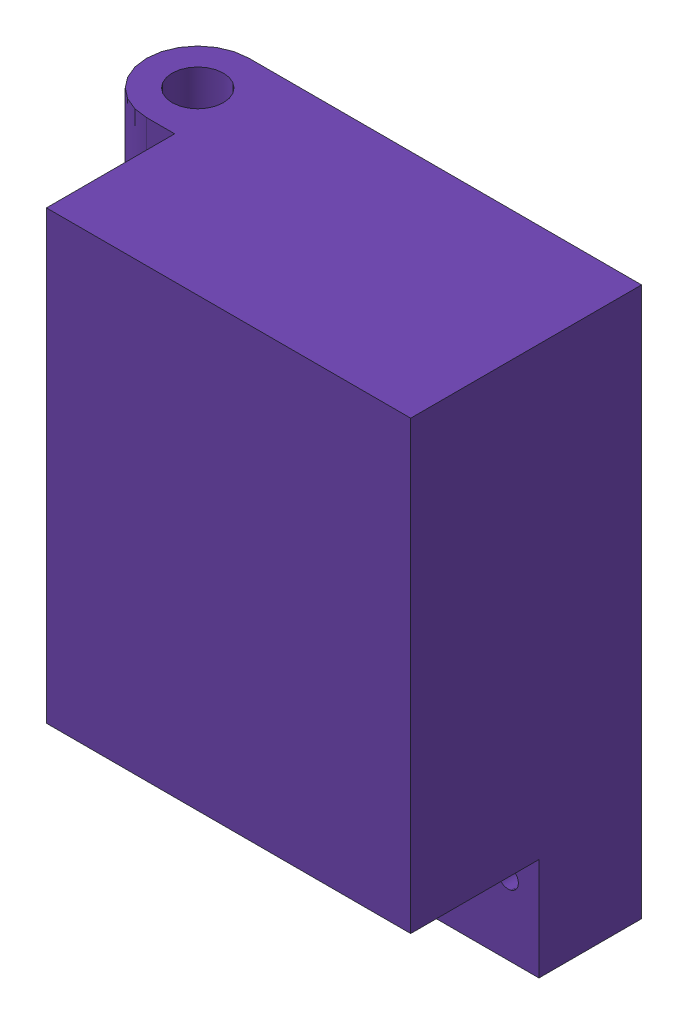
SolidWorks assembly LoRa_Balloon, configuration Default. Lengths in mm.
Overall size (43.25 53.5 22.5).
126 component instances, 18 part files, 6 mates.
Components (placement in the parent):
- LoRa_Balloon.step-1: LoRa_Balloon.step [Default] at origin size (30 47 5)
  - TSX-3225.step-1: TSX-3225.step [Default] at (108.5095 -135.9864 1.65) x (1 0 0) z (0 -1 0) size (3.2 0.6 2.5)
    - SOLID.step-1: SOLID.step [Default] at origin size (3.2 0.6 2.5)
  - ublox_MAX_M8C.step-1: ublox_MAX_M8C.step [Default] at (106.83 -119.32 -0.05) x (0 -1 0) z (1 0 0) size (9.72 2.21 10.1)
    - COMPOUND.step-1: COMPOUND.step [Default] at origin size (9.72 2.21 10.1)
  - 0402_C.step-1: 0402_C.step [Default] at (107.16 -138.61 1.65) x (1 0 0) z (0 -1 0) size (0.9 0.3 0.5)
    - COMPOUND-0.step-1: COMPOUND-0.step [Default] at origin size (0.9 0.3 0.5)
  - SC-70.step-1: SC-70.step [Default] at (116.0558 -117.9372 1.65) x (1 0 0) z (0 -1 0) size (2.05 0.9 2.1)
    - COMPOUND-1.step-1: COMPOUND-1.step [Default] at origin size (2.05 0.9 2.1)
  - DFN-8.step-1: DFN-8.step [Default] at (122.5624 -127.2782 1.65) x (-1 0 0) z (0 1 0) size (2.02 0.86 2)
    - COMPOUND-2.step-1: COMPOUND-2.step [Default] at origin size (2.02 0.86 2)
  - DFN-8.step-2: DFN-8.step [Default] at (121.4762 -122.3263 1.65) x (1 0 0) z (0 -1 0) size (2.02 0.86 2)
    - COMPOUND-2.step-1: COMPOUND-2.step [Default] at origin size (2.02 0.86 2)
  - SAW_filter.step-1: SAW_filter.step [Default] at (115.95 -106.9 1.65) x (1 0 0) z (0 -1 0) size (3.02 1.11 3.02)
    - COMPOUND-3.step-1: COMPOUND-3.step [Default] at origin size (3.02 1.11 3.02)
  - XCL205.step-1: XCL205.step [Default] at (125.85 -135.26 1.65) x (0 1 0) z (1 0 0) size (2.5 1.05 2)
    - COMPOUND-4.step-1: COMPOUND-4.step [Default] at origin size (2.5 1.05 2)
  - 7A_crystal.step-1: 7A_crystal.step [Default] at (104.33 -136.88 -0.05) x (1 0 0) z (0 1 0) size (5 1.2 3.2)
    - SOLID-5.step-1: SOLID-5.step [Default] at origin size (5 1.2 3.2)
  - Chip_antenna.step-1: Chip_antenna.step [Default] at (103.53 -105.26 -0.05) x (0 -1 0) z (1 0 0) size (7 0.85 2)
    - COMPOUND-6.step-1: COMPOUND-6.step [Default] at origin size (7 0.85 2)
  - Chip_antenna.step-2: Chip_antenna.step [Default] at (125.75 -102.8 1.65) x (-1 0 0) z (0 1 0) size (7 0.85 2)
    - COMPOUND-6.step-1: COMPOUND-6.step [Default] at origin size (7 0.85 2)
  - SX1272.step-1: SX1272.step [Default] at (115.3441 -133.9037 1.65) x (1 0 0) z (0 -1 0) size (6.02 0.92 6.02)
    - COMPOUND-7.step-1: COMPOUND-7.step [Default] at origin size (6.02 0.92 6.02)
  - 0402_C.step-2: 0402_C.step [Default] at (109.29 -133.64 1.65) x (0 -1 0) z (-1 0 0) size (0.9 0.3 0.5)
    - COMPOUND-0.step-1: COMPOUND-0.step [Default] at origin size (0.9 0.3 0.5)
  - ATMega-328P-MMH.step-1: ATMega-328P-MMH.step [Default] at (105.5 -131.22 -0.05) x (1 0 0) z (0 1 0) size (4.02 0.92 4.02)
    - COMPOUND-8.step-1: COMPOUND-8.step [Default] at origin size (4.02 0.92 4.02)
  - 0805_C.step-1: 0805_C.step [Default] at (109.5737 -129.9064 1.65) x (0 1 0) z (1 0 0) size (1.55 0.8 1.25)
    - COMPOUND-9.step-1: COMPOUND-9.step [Default] at origin size (1.55 0.8 1.25)
  - 0402_C.step-3: 0402_C.step [Default] at (120.5719 -118.3812 1.65) x (0 1 0) z (1 0 0) size (0.9 0.3 0.5)
    - COMPOUND-0.step-1: COMPOUND-0.step [Default] at origin size (0.9 0.3 0.5)
  - 0402_C.step-4: 0402_C.step [Default] at (122.8782 -119.8472 1.65) x (0 1 0) z (1 0 0) size (0.9 0.3 0.5)
    - COMPOUND-0.step-1: COMPOUND-0.step [Default] at origin size (0.9 0.3 0.5)
  - 0402_C.step-5: 0402_C.step [Default] at (124.1736 -119.8472 1.65) x (0 1 0) z (1 0 0) size (0.9 0.3 0.5)
    - COMPOUND-0.step-1: COMPOUND-0.step [Default] at origin size (0.9 0.3 0.5)
  - 0402_C.step-6: 0402_C.step [Default] at (113.8714 -116.9872 1.65) x (-1 0 0) z (0 1 0) size (0.9 0.3 0.5)
    - COMPOUND-0.step-1: COMPOUND-0.step [Default] at origin size (0.9 0.3 0.5)
  - 0603_C.step-1: 0603_C.step [Default] at (125.93 -132.62 1.65) x (1 0 0) z (0 -1 0) size (1.2 0.8 0.8)
    - COMPOUND-10.step-1: COMPOUND-10.step [Default] at origin size (1.2 0.8 0.8)
  - 0603_C.step-2: 0603_C.step [Default] at (123.59 -138.21 1.65) x (-1 0 0) z (0 1 0) size (1.2 0.8 0.8)
    - COMPOUND-10.step-1: COMPOUND-10.step [Default] at origin size (1.2 0.8 0.8)
  - 0402_C.step-7: 0402_C.step [Default] at (103.98 -126.99 -0.05) x (-1 0 0) z (0 -1 0) size (0.9 0.3 0.5)
    - COMPOUND-0.step-1: COMPOUND-0.step [Default] at origin size (0.9 0.3 0.5)
  - 0402_C.step-8: 0402_C.step [Default] at (103.59 -139.5 -0.05) x (0 1 0) z (-1 0 0) size (0.9 0.3 0.5)
    - COMPOUND-0.step-1: COMPOUND-0.step [Default] at origin size (0.9 0.3 0.5)
  - 0402_C.step-9: 0402_C.step [Default] at (104.89 -139.5 -0.05) x (0 1 0) z (-1 0 0) size (0.9 0.3 0.5)
    - COMPOUND-0.step-1: COMPOUND-0.step [Default] at origin size (0.9 0.3 0.5)
  - 0402_C.step-10: 0402_C.step [Default] at (110.04 -127.13 -0.05) x (0 -1 0) z (1 0 0) size (0.9 0.3 0.5)
    - COMPOUND-0.step-1: COMPOUND-0.step [Default] at origin size (0.9 0.3 0.5)
  - 0402_L.step-1: 0402_L.step [Default] at (113.6276 -121.7857 1.65) x (0 -1 0) z (-1 0 0) size (0.9 0.3 0.5)
    - COMPOUND-11.step-1: COMPOUND-11.step [Default] at origin size (0.9 0.3 0.5)
  - 0402_L.step-2: 0402_L.step [Default] at (113.0942 -129.3519 1.65) x (0 -1 0) z (-1 0 0) size (0.9 0.3 0.5)
    - COMPOUND-11.step-1: COMPOUND-11.step [Default] at origin size (0.9 0.3 0.5)
  - 0402_C.step-11: 0402_C.step [Default] at (117.1611 -120.1876 1.65) x (1 0 0) z (0 -1 0) size (0.9 0.3 0.5)
    - COMPOUND-0.step-1: COMPOUND-0.step [Default] at origin size (0.9 0.3 0.5)
  - 0402_C.step-12: 0402_C.step [Default] at (111.2196 -130.757 1.65) x (0 1 0) z (1 0 0) size (0.9 0.3 0.5)
    - COMPOUND-0.step-1: COMPOUND-0.step [Default] at origin size (0.9 0.3 0.5)
  - 0402_C.step-13: 0402_C.step [Default] at (117.0293 -121.7606 1.65) x (-0.707107 0.707107 0) z (0.707107 0.707107 0) size (0.9 0.3 0.5)
    - COMPOUND-0.step-1: COMPOUND-0.step [Default] at origin size (0.9 0.3 0.5)
  - 0402_C.step-14: 0402_C.step [Default] at (110.8869 -132.3542 1.65) x (-1 0 0) z (0 1 0) size (0.9 0.3 0.5)
    - COMPOUND-0.step-1: COMPOUND-0.step [Default] at origin size (0.9 0.3 0.5)
  - 0402_C.step-15: 0402_C.step [Default] at (111.6739 -128.28 1.65) x (-1 0 0) z (0 1 0) size (0.9 0.3 0.5)
    - COMPOUND-0.step-1: COMPOUND-0.step [Default] at origin size (0.9 0.3 0.5)
  - 0402_C.step-16: 0402_C.step [Default] at (110.8916 -133.4108 1.65) x (-1 0 0) z (0 1 0) size (0.9 0.3 0.5)
    - COMPOUND-0.step-1: COMPOUND-0.step [Default] at origin size (0.9 0.3 0.5)
  - 0402_C.step-17: 0402_C.step [Default] at (111.6739 -129.357 1.65) x (-1 0 0) z (0 1 0) size (0.9 0.3 0.5)
    - COMPOUND-0.step-1: COMPOUND-0.step [Default] at origin size (0.9 0.3 0.5)
  - 0402_C.step-18: 0402_C.step [Default] at (122.95 -135.86 1.65) x (1 0 0) z (0 -1 0) size (0.9 0.3 0.5)
    - COMPOUND-0.step-1: COMPOUND-0.step [Default] at origin size (0.9 0.3 0.5)
  - 0402_C.step-19: 0402_C.step [Default] at (124.6105 -122.5316 1.65) x (0 1 0) z (1 0 0) size (0.9 0.3 0.5)
    - COMPOUND-0.step-1: COMPOUND-0.step [Default] at origin size (0.9 0.3 0.5)
  - 0402_C.step-20: 0402_C.step [Default] at (125.0605 -123.9265 1.65) x (1 0 0) z (0 -1 0) size (0.9 0.3 0.5)
    - COMPOUND-0.step-1: COMPOUND-0.step [Default] at origin size (0.9 0.3 0.5)
  - 0402_C.step-21: 0402_C.step [Default] at (124.6105 -125.3366 1.65) x (0 1 0) z (1 0 0) size (0.9 0.3 0.5)
    - COMPOUND-0.step-1: COMPOUND-0.step [Default] at origin size (0.9 0.3 0.5)
  - 0402_C.step-22: 0402_C.step [Default] at (125.276 -129.0141 1.65) x (0 1 0) z (1 0 0) size (0.9 0.3 0.5)
    - COMPOUND-0.step-1: COMPOUND-0.step [Default] at origin size (0.9 0.3 0.5)
  - 0402_C.step-23: 0402_C.step [Default] at (109.06 -138.03 1.65) x (1 0 0) z (0 -1 0) size (0.9 0.3 0.5)
    - COMPOUND-0.step-1: COMPOUND-0.step [Default] at origin size (0.9 0.3 0.5)
  - 0402_C.step-24: 0402_C.step [Default] at (120.5135 -129.5805 1.65) x (0 -1 0) z (-1 0 0) size (0.9 0.3 0.5)
    - COMPOUND-0.step-1: COMPOUND-0.step [Default] at origin size (0.9 0.3 0.5)
  - 0402_C.step-25: 0402_C.step [Default] at (113.6957 -127.9549 1.65) x (-1 0 0) z (0 1 0) size (0.9 0.3 0.5)
    - COMPOUND-0.step-1: COMPOUND-0.step [Default] at origin size (0.9 0.3 0.5)
  - 0402_C.step-26: 0402_C.step [Default] at (121.5244 -129.5805 1.65) x (0 -1 0) z (-1 0 0) size (0.9 0.3 0.5)
    - COMPOUND-0.step-1: COMPOUND-0.step [Default] at origin size (0.9 0.3 0.5)
  - 0402_C.step-27: 0402_C.step [Default] at (114.1457 -126.5499 1.65) x (0 -1 0) z (-1 0 0) size (0.9 0.3 0.5)
    - COMPOUND-0.step-1: COMPOUND-0.step [Default] at origin size (0.9 0.3 0.5)
  - 0402_C.step-28: 0402_C.step [Default] at (117.4477 -127.0807 1.65) x (0 1 0) z (1 0 0) size (0.9 0.3 0.5)
    - COMPOUND-0.step-1: COMPOUND-0.step [Default] at origin size (0.9 0.3 0.5)
  - 0402_C.step-29: 0402_C.step [Default] at (118.9103 -127.5282 1.65) x (1 0 0) z (0 -1 0) size (0.9 0.3 0.5)
    - COMPOUND-0.step-1: COMPOUND-0.step [Default] at origin size (0.9 0.3 0.5)
  - 0402_C.step-30: 0402_C.step [Default] at (113.6881 -123.3804 1.65) x (-1 0 0) z (0 1 0) size (0.9 0.3 0.5)
    - COMPOUND-0.step-1: COMPOUND-0.step [Default] at origin size (0.9 0.3 0.5)
  - 0402_C.step-31: 0402_C.step [Default] at (114.674 -121.7857 1.65) x (0 -1 0) z (-1 0 0) size (0.9 0.3 0.5)
    - COMPOUND-0.step-1: COMPOUND-0.step [Default] at origin size (0.9 0.3 0.5)
  - 0402_C.step-32: 0402_C.step [Default] at (113.7067 -120.1825 1.65) x (-1 0 0) z (0 1 0) size (0.9 0.3 0.5)
    - COMPOUND-0.step-1: COMPOUND-0.step [Default] at origin size (0.9 0.3 0.5)
  - 0402_C.step-33: 0402_C.step [Default] at (118.2148 -116.9872 1.65) x (1 0 0) z (0 -1 0) size (0.9 0.3 0.5)
    - COMPOUND-0.step-1: COMPOUND-0.step [Default] at origin size (0.9 0.3 0.5)
  - 0402_C.step-34: 0402_C.step [Default] at (118.23 -115.3 1.65) x (0 -1 0) z (-1 0 0) size (0.9 0.3 0.5)
    - COMPOUND-0.step-1: COMPOUND-0.step [Default] at origin size (0.9 0.3 0.5)
  - 0402_L.step-3: 0402_L.step [Default] at (119.1241 -122.0774 1.65) x (-1 0 0) z (0 1 0) size (0.9 0.3 0.5)
    - COMPOUND-11.step-1: COMPOUND-11.step [Default] at origin size (0.9 0.3 0.5)
  - 0402_L.step-4: 0402_L.step [Default] at (123.5285 -121.6274 1.65) x (0 -1 0) z (-1 0 0) size (0.9 0.3 0.5)
    - COMPOUND-11.step-1: COMPOUND-11.step [Default] at origin size (0.9 0.3 0.5)
  - 0402_L.step-5: 0402_L.step [Default] at (114.1457 -129.3549 1.65) x (0 -1 0) z (-1 0 0) size (0.9 0.3 0.5)
    - COMPOUND-11.step-1: COMPOUND-11.step [Default] at origin size (0.9 0.3 0.5)
  - 0402_L.step-6: 0402_L.step [Default] at (124.6105 -127.079 1.65) x (0 1 0) z (1 0 0) size (0.9 0.3 0.5)
    - COMPOUND-11.step-1: COMPOUND-11.step [Default] at origin size (0.9 0.3 0.5)
  - 0402_L.step-7: 0402_L.step [Default] at (115.7619 -127.8482 1.65) x (-0.707107 -0.707107 0) z (-0.707107 0.707107 0) size (0.9 0.3 0.5)
    - COMPOUND-11.step-1: COMPOUND-11.step [Default] at origin size (0.9 0.3 0.5)
  - 0402_L.step-8: 0402_L.step [Default] at (120.5135 -127.9778 1.65) x (0 1 0) z (1 0 0) size (0.9 0.3 0.5)
    - COMPOUND-11.step-1: COMPOUND-11.step [Default] at origin size (0.9 0.3 0.5)
  - 0402_L.step-9: 0402_L.step [Default] at (114.1457 -124.7901 1.65) x (0 -1 0) z (-1 0 0) size (0.9 0.3 0.5)
    - COMPOUND-11.step-1: COMPOUND-11.step [Default] at origin size (0.9 0.3 0.5)
  - 0402_R.step-1: 0402_R.step [Default] at (120.5719 -120.1338 1.65) x (0 -1 0) z (-1 0 0) size (0.9 0.3 0.5)
    - COMPOUND-12.step-1: COMPOUND-12.step [Default] at origin size (0.9 0.3 0.5)
  - 0402_R.step-2: 0402_R.step [Default] at (111.1917 -137.3072 1.65) x (0 1 0) z (1 0 0) size (0.9 0.3 0.5)
    - COMPOUND-12.step-1: COMPOUND-12.step [Default] at origin size (0.9 0.3 0.5)
  - 0402_R.step-3: 0402_R.step [Default] at (123.9146 -129.4637 1.65) x (-1 0 0) z (0 1 0) size (0.9 0.3 0.5)
    - COMPOUND-12.step-1: COMPOUND-12.step [Default] at origin size (0.9 0.3 0.5)
  - COMPOUND-13.step-1: COMPOUND-13.step [Default] at origin size (30 47 1.6)
- Mk3_Enclosure-1: Mk3_Enclosure [Default] at (115 -98.5 1.6) x (1 0 0) z (0 0 -1) size (43.25 53.5 22.5)
- Mk3_Lid-1: Mk3_Lid [Default] at (115 -142 2.85) x (-1 0 0) z (0 0 1) size (35.5 10 12.5) (hidden)
Mates (geometry in assembly coordinates):
- Coincident1: coincident anti-aligned: plane of LoRa_Balloon.step-1/COMPOUND-13.step-1 through (115 -124.1922 0) normal (0 0 -1); plane of Mk3_Enclosure-1 through (104.75 -142 0) normal (0 0 1)
- Distance1: distance = 0.25 mm anti-aligned: plane of LoRa_Balloon.step-1/COMPOUND-13.step-1 through (130 -101 0) normal (1 0 0); plane of Mk3_Enclosure-1 through (130.25 -142 0) normal (-1 0 0)
- Coincident3: coincident aligned: plane of LoRa_Balloon.step-1/COMPOUND-13.step-1 through (130 -142 0) normal (0 -1 0); plane of Mk3_Enclosure-1 through (115 -142 1.6) normal (0 -1 0)
- Coincident7: coincident anti-aligned: plane of Mk3_Enclosure-1 through (99.75 -142 -3.4) normal (0 0 1); plane of Mk3_Lid-1 through (132.75 -152 -3.4) normal (0 0 -1)
- Coincident8: coincident aligned: plane of Mk3_Enclosure-1 through (97.25 -142 -5.9) normal (-1 0 0); plane of Mk3_Lid-1 through (97.25 -152 9.1) normal (-1 0 0)
- Coincident11: coincident anti-aligned: plane of Mk3_Enclosure-1 through (115 -142 1.6) normal (0 -1 0); plane of Mk3_Lid-1 through (115 -142 2.85) normal (0 1 0)
